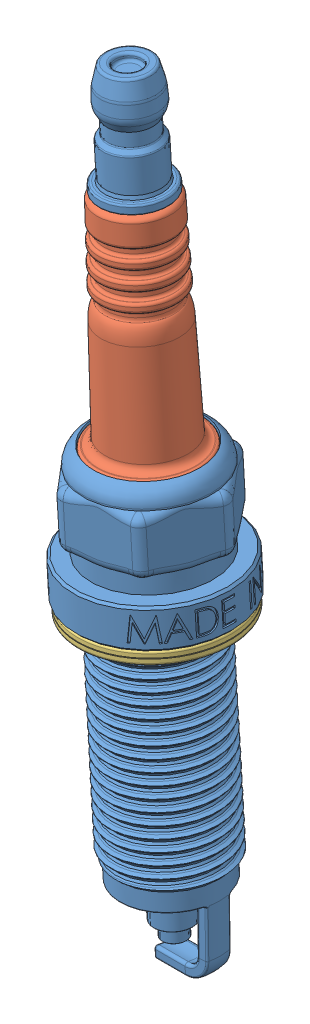
SolidWorks assembly spark plug 1, configuration Default. Lengths in mm.
Overall size (22.33 85.33 17).
3 component instances, 3 part files, 5 mates.
Components (placement in the parent):
- Spark Plug - Main Body-1: Spark Plug - Main Body [Default] at (38.6493 83.9767 79.5249) x (-0.99798 -0.063524 0) z (0 0 1) size (17 84.43 17)
- Insulator-1: Insulator [Default] at (41.8001 34.4769 79.5249) x (0.835478 0.05318 -0.546944) z (0.545839 0.034744 0.837169) size (11.36 25.64 11.36)
- Washer-1: Washer [Default] at (41.8255 34.0777 79.5249) x (-0.99798 -0.063524 0) z (0 0 1) size (16.6 1.4 16.6)
Mates (geometry in assembly coordinates):
- Coincident1: coincident anti-aligned: plane of Spark Plug - Main Body-1 through (41.8963 52.0245 79.5249) normal (0 -1 0); plane of Insulator-1 through (37.1412 52.0245 76.4183) normal (0 1 0)
- Concentric1: concentric aligned: cylinder of Spark Plug - Main Body-1 through (41.8963 14.3245 79.5249) axis (0 -1 0) radius 2.5; cylinder of Insulator-1 through (41.8963 52.0255 79.5249) axis (0 -1 0) radius 2.525
- Coincident2: coincident anti-aligned: plane of Spark Plug - Main Body-1 through (41.8963 64.3245 79.5249) normal (0 1 0); plane of Washer-1 through (41.8963 64.3245 79.5249) normal (0 -1 0)
- Concentric2: concentric aligned: cylinder of Spark Plug - Main Body-1 through (41.8963 81.7245 79.5249) axis (0 1 0) radius 2.1; circle of Washer-1
- Tangent1: tangent: face of Spark Plug - Main Body-1; plane of assembly
